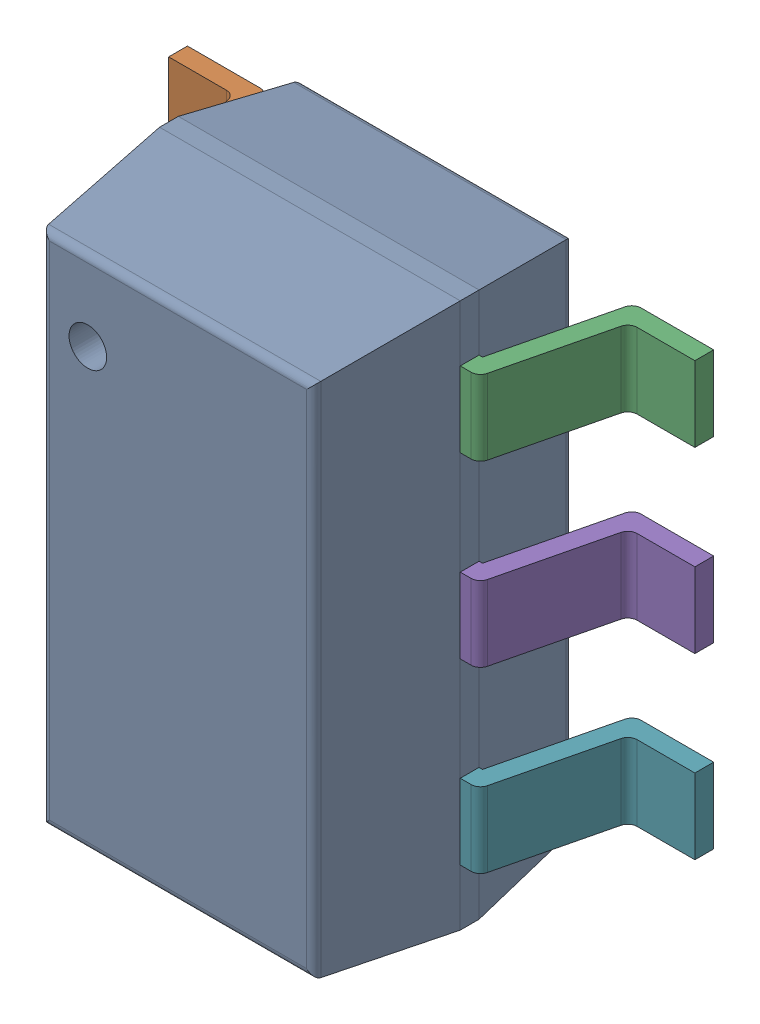
SolidWorks assembly IC21_1.step, configuration Default. Lengths in mm.
Overall size (2.8 2.9 1.45).
3 component instances, 2 part files, 0 mates.
Components (placement in the parent):
- 9798852320_1.step-3: 9798852320_1.step [Default] at (496.9662 325.2319 0) size (2.8 2.9 1.45)
  - Body-7_1.step-3: Body-7_1.step [Default] at origin size (1.6 2.9 1.38)
  - PinsArrayLR-8_1.step-3: PinsArrayLR-8_1.step [Default] at origin size (2.8 2.3 0.75)
